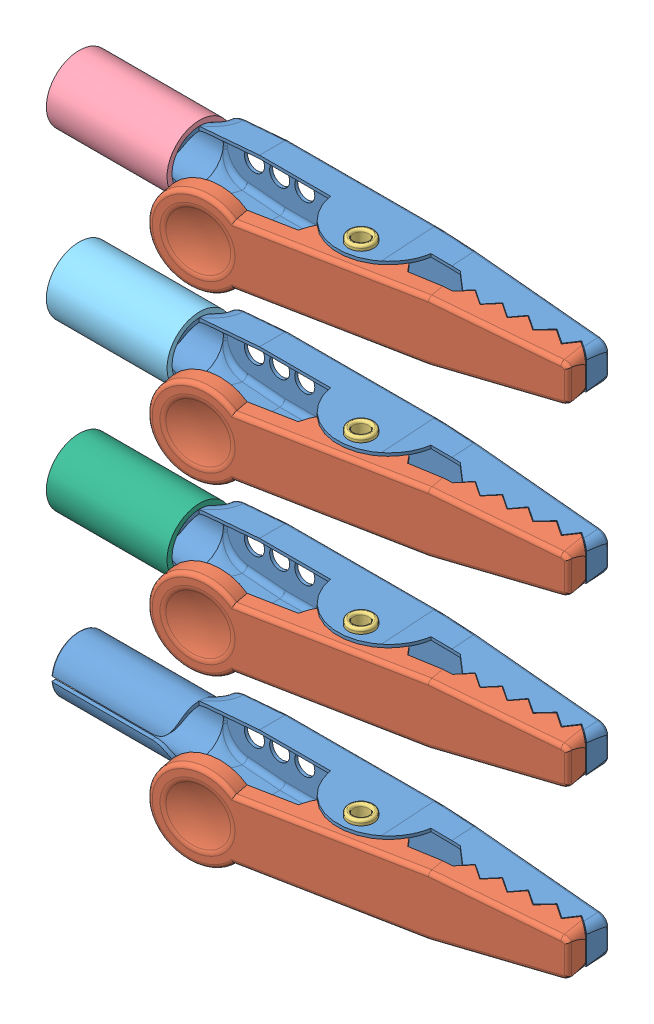
SolidWorks assembly Crock Assem Ani, configuration Default. Lengths in mm.
Overall size (50.03 58.35 12.88).
15 component instances, 6 part files, 35 mates.
Components (placement in the parent):
- Bottom Clip-1: Bottom Clip [Default] at (18.9446 22.5579 37.1326) size (50.03 7.06 7.05)
- Top Clip-1: Top Clip [Default] at (18.9716 22.5579 37.1041) x (0.999986 0 0.005236) z (-0.005236 0 0.999986) size (35.33 8.5 9.52)
- Pin-1: Pin [Default] at (24.3873 25.8079 42.2763) x (1 0 0) z (0 -1 0) size (2.5 2.5 7.5)
- Bottom Clip-2: Bottom Clip [Default] at (18.9446 6.0579 37.1326) size (50.03 7.06 7.05)
- Bottom Clip-3: Bottom Clip [Default] at (18.9446 -10.4421 37.1326) size (50.03 7.06 7.05)
- Pin-2: Pin [Default] at (24.3873 9.3079 42.2763) x (1 0 0) z (0 -1 0) size (2.5 2.5 7.5)
- Pin-3: Pin [Default] at (24.3873 -7.1921 42.2763) x (1 0 0) z (0 -1 0) size (2.5 2.5 7.5)
- Top Clip-2: Top Clip [Default] at (18.9716 6.0579 37.1041) x (0.999986 0 0.005236) z (-0.005236 0 0.999986) size (35.33 8.5 9.52)
- Top Clip-3: Top Clip [Default] at (18.9716 -10.4421 37.1041) x (0.999986 0 0.005236) z (-0.005236 0 0.999986) size (35.33 8.5 9.52)
- Bottom Clip-4: Bottom Clip [Default] at (18.9446 -26.9421 37.1326) size (50.03 7.06 7.05)
- Pin-4: Pin [Default] at (24.3873 -23.6921 42.2763) x (1 0 0) z (0 -1 0) size (2.5 2.5 7.5)
- Top Clip-4: Top Clip [Default] at (18.9716 -26.9421 37.1041) x (0.999986 0 0.005236) z (-0.005236 0 0.999986) size (35.33 8.5 9.52)
- Cover Red-1: Cover Red [Default] at (5.9446 22.5579 39.8826) x (0 0.696407 -0.717647) z (-1 0 0) size (6.5 6.5 12)
- Cover Black-1: Cover Black [Default] at (-6.0554 6.0579 39.8826) x (0 0 -1) z (1 0 0) size (6.5 6.5 12)
- Cover Green-1: Cover Green [Default] at (-6.0554 -10.4421 39.8826) x (0 0 -1) z (1 0 0) size (6.5 6.5 12)
Mates (geometry in assembly coordinates):
- Coincident2: coincident: plane of Bottom Clip-1 through (-6.0554 19.6079 48.1326) normal (0 1 0); plane of Top Clip-1 through (5.8065 19.6079 38.4687) normal (0 -1 0)
- Concentric2: concentric: cylinder of Bottom Clip-1 through (24.3873 29.3079 42.2763) axis (0 -1 0) radius 1; cylinder of Pin-1 through (24.3873 19.3079 42.2763) axis (0 1 0) radius 1
- Coincident3: coincident: plane of Bottom Clip-1 through (-6.0554 19.3079 48.1326) normal (0 -1 0); plane of Pin-1 through (24.3873 19.3079 42.2763) normal (0 1 0)
- Concentric3: concentric: cylinder of Top Clip-1 through (24.3873 29.3079 42.2763) axis (0 -1 0) radius 1; cylinder of Pin-1 through (24.3873 19.3079 42.2763) axis (0 1 0) radius 1
- Concentric4: concentric: cylinder of Bottom Clip-2 through (24.3873 12.8079 42.2763) axis (0 -1 0) radius 1; cylinder of Pin-2 through (24.3873 2.8079 42.2763) axis (0 1 0) radius 1
- Coincident4: coincident: plane of Bottom Clip-2 through (-6.0554 9.3079 48.1326) normal (0 1 0); plane of Pin-2 through (24.3873 9.3079 42.2763) normal (0 -1 0)
- Concentric5: concentric: cylinder of Bottom Clip-3 through (24.3873 -3.6921 42.2763) axis (0 -1 0) radius 1; cylinder of Pin-3 through (24.3873 -13.6921 42.2763) axis (0 1 0) radius 1
- Coincident5: coincident: plane of Bottom Clip-3 through (-6.0554 -13.6921 48.1326) normal (0 -1 0); plane of Pin-3 through (24.3873 -13.6921 42.2763) normal (0 1 0)
- Coincident6: coincident: plane of Bottom Clip-3 through (-6.0554 -13.3921 48.1326) normal (0 1 0); plane of Top Clip-3 through (5.8065 -13.3921 38.4687) normal (0 -1 0)
- Coincident7: coincident: cylinder of Pin-3 through (24.3873 -13.6921 42.2763) axis (0 1 0) radius 1; circle of Top Clip-3
- Coincident8: coincident: plane of Bottom Clip-2 through (-6.0554 3.1079 48.1326) normal (0 1 0); plane of Top Clip-2 through (5.8065 3.1079 38.4687) normal (0 -1 0)
- Concentric6: concentric: cylinder of Pin-2 through (24.3873 2.8079 42.2763) axis (0 1 0) radius 1; cylinder of Top Clip-2 through (24.3873 12.8079 42.2763) axis (0 -1 0) radius 1
- Coincident9: coincident: plane of Bottom Clip-1 through (18.9446 22.5579 37.1326) normal (0 0 -1); plane of Bottom Clip-2 through (18.9446 6.0579 37.1326) normal (0 0 -1)
- Coincident10: coincident: plane of Bottom Clip-2 through (18.9446 6.0579 37.1326) normal (0 0 -1); plane of Bottom Clip-3 through (18.9446 -10.4421 37.1326) normal (0 0 -1)
- Distance1: distance = 10 mm: plane of Bottom Clip-1 through (-6.0554 19.3079 48.1326) normal (0 -1 0); plane of Bottom Clip-2 through (-6.0554 9.3079 48.1326) normal (0 1 0)
- Distance2: distance = 10 mm: plane of Bottom Clip-2 through (-6.0554 2.8079 48.1326) normal (0 -1 0); plane of Bottom Clip-3 through (-6.0554 -7.1921 48.1326) normal (0 1 0)
- Coincident13: coincident: plane of Bottom Clip-1 through (-6.0554 25.8079 48.1326) normal (-1 0 0); plane of Bottom Clip-2 through (-6.0554 9.3079 48.1326) normal (-1 0 0)
- Coincident14: coincident: circle of Bottom Clip-2; plane of Bottom Clip-3 through (-6.0554 -7.1921 48.1326) normal (-1 0 0)
- Coincident15: coincident: circle of Bottom Clip-4; cylinder of Pin-4 through (24.3873 -30.1921 42.2763) axis (0 1 0) radius 1
- Coincident16: coincident: plane of Bottom Clip-4 through (-6.0554 -30.1921 48.1326) normal (0 -1 0); plane of Pin-4 through (24.3873 -30.1921 42.2763) normal (0 1 0)
- Concentric7: concentric: cylinder of Pin-4 through (24.3873 -30.1921 42.2763) axis (0 1 0) radius 1; cylinder of Top Clip-4 through (24.3873 -20.1921 42.2763) axis (0 -1 0) radius 1
- Coincident17: coincident: plane of Bottom Clip-4 through (-6.0554 -29.8921 48.1326) normal (0 1 0); plane of Top Clip-4 through (5.8065 -29.8921 38.4687) normal (0 -1 0)
- Coincident18: coincident: plane of Bottom Clip-3 through (18.9446 -10.4421 37.1326) normal (0 0 -1); plane of Bottom Clip-4 through (18.9446 -26.9421 37.1326) normal (0 0 -1)
- Coincident19: coincident: plane of Bottom Clip-3 through (-6.0554 -7.1921 48.1326) normal (-1 0 0); plane of Bottom Clip-4 through (-6.0554 -23.6921 48.1326) normal (-1 0 0)
- Distance3: distance = 10 mm: plane of Bottom Clip-3 through (-6.0554 -13.6921 48.1326) normal (0 -1 0); plane of Bottom Clip-4 through (-6.0554 -23.6921 48.1326) normal (0 1 0)
- Concentric9: concentric: cylinder of Bottom Clip-1 through (5.9446 22.5579 39.8826) axis (-1 0 0) radius 2.75; cylinder of Cover Red-1 through (5.9446 22.5579 39.8826) axis (-1 0 0) radius 2.75
- Coincident21: coincident: plane of Bottom Clip-1 through (-6.0554 25.8079 48.1326) normal (-1 0 0); plane of Cover Red-1 through (-6.0554 22.5579 39.8826) normal (-1 0 0)
- Concentric10: concentric: cylinder of Bottom Clip-2 through (5.9446 6.0579 39.8826) axis (-1 0 0) radius 2.75; cylinder of Cover Black-1 through (-6.0554 6.0579 39.8826) axis (1 0 0) radius 2.75
- Concentric11: concentric: cylinder of Bottom Clip-3 through (5.9446 -10.4421 39.8826) axis (-1 0 0) radius 2.75; cylinder of Cover Green-1 through (-6.0554 -10.4421 39.8826) axis (1 0 0) radius 2.75
- Coincident22: coincident: plane of Bottom Clip-2 through (-6.0554 9.3079 48.1326) normal (-1 0 0); plane of Cover Black-1 through (-6.0554 6.0579 39.8826) normal (-1 0 0)
- Coincident23: coincident: plane of Bottom Clip-3 through (-6.0554 -7.1921 48.1326) normal (-1 0 0); plane of Cover Green-1 through (-6.0554 -10.4421 39.8826) normal (-1 0 0)
- Angle6: planar angle = 0.005236 rad: plane of Bottom Clip-1 through (42.6012 29.3079 38.5458) normal (-0.536078 0 0.844169); plane of Top Clip-1 through (25.1811 29.3079 27.438) normal (0.540491 0 -0.84135)
- Angle7: planar angle = 0.005236 rad: plane of Top Clip-2 through (25.1811 12.8079 27.438) normal (0.540491 0 -0.84135); plane of Bottom Clip-2 through (42.6012 12.8079 38.5458) normal (-0.536078 0 0.844169)
- Angle8: planar angle = 0.005236 rad: plane of Bottom Clip-3 through (42.6012 -3.6921 38.5458) normal (-0.536078 0 0.844169); plane of Top Clip-3 through (25.1811 -3.6921 27.438) normal (0.540491 0 -0.84135)
- Angle9: planar angle = 0.005236 rad: plane of Top Clip-4 through (25.1811 -20.1921 27.438) normal (0.540491 0 -0.84135); plane of Bottom Clip-4 through (42.6012 -20.1921 38.5458) normal (-0.536078 0 0.844169)
